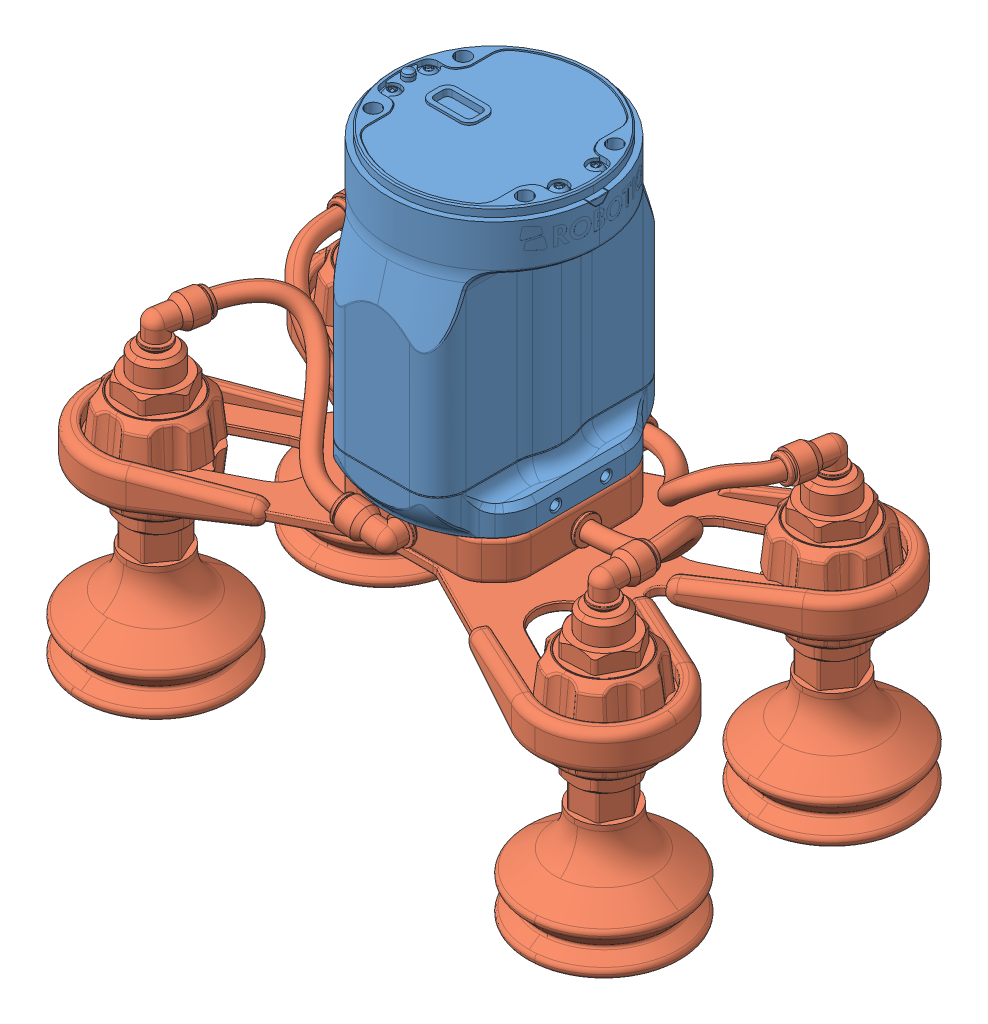
SolidWorks assembly EPick-Four_20Vacuum_20Cup_20Assy_20190617, configuration Default. Lengths in mm.
Overall size (217.84 186.43 144.51).
3 component instances, 2 part files, 0 mates.
Components (placement in the parent):
- EPick-Four_20Vacuum_20Cup_20Assy_20190617.STEP-1: EPick-Four_20Vacuum_20Cup_20Assy_20190617.STEP [Default] at origin size (217.84 186.43 144.51)
  - EPick.STEP-1: EPick.STEP [Default] at (0 6 0) x (-1 0 0) z (0 0 1) size (75.02 104.7 86.14)
  - ENSEMBLE 4 VENTOUSES.STEP-1: ENSEMBLE 4 VENTOUSES.STEP [Default] at (0 -7 0) size (217.84 109.35 144.51)
